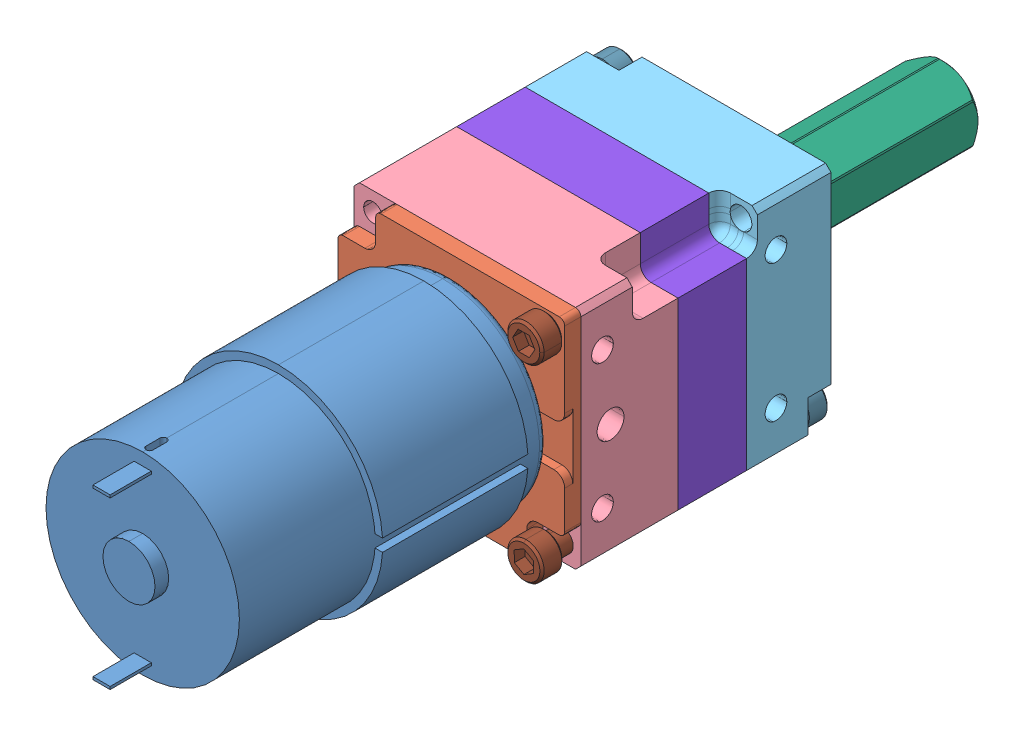
SolidWorks assembly VersaPlanetary v1 Single Stage 10_1 with RS 550 .step, configuration Default. Lengths in mm.
Overall size (42.53 42 155.97).
31 component instances, 20 part files, 0 mates.
Components (placement in the parent):
- 217-2625-100.step-1: 217-2625-100.step [Default] at (0 0 -18.467) x (0 1 0) z (0 0 1) size (39.22 38.88 12.7)
  - 217-2625-008 Rev1.step-1: 217-2625-008 Rev1.step [Default] at origin size (34.7 34.7 4.7)
  - 217-2625-010 Rev1.step-1: 217-2625-010 Rev1.step [Default] at (0 10.193 3.65) x (0.999813 0.019336 0) z (0 0 1) size (4 4 12)
  - 217-2625-010 Rev1.step-2: 217-2625-010 Rev1.step [Default] at (8.691 -5.3258 3.65) size (4 4 12)
  - 217-2625-010 Rev1.step-3: 217-2625-010 Rev1.step [Default] at (-8.691 -5.3258 3.65) size (4 4 12)
  - 217-2625-005 Rev1_Planet_Revolving_Follower01.step-1: 217-2625-005 Rev1_Planet_Revolving_Follower01.step [Default] at (8.691 -5.3258 6.35) x (0.932816 0.360354 0) z (0 0 1) size (16.89 16.89 8)
  - 217-2625-005 Rev1_Planet_Revolving_Follower01.step-2: 217-2625-005 Rev1_Planet_Revolving_Follower01.step [Default] at (-8.691 -5.3258 6.35) x (-0.932788 -0.360426 0) z (0 0 1) size (16.89 16.89 8)
  - 217-2625-005 Rev1_Planet_Revolving_Follower01.step-3: 217-2625-005 Rev1_Planet_Revolving_Follower01.step [Default] at (0 10.193 6.35) x (0.893583 0.448898 0) z (0 0 1) size (16.89 16.89 8)
- 217-2625-001 Rev1.step-1: 217-2625-001 Rev1.step [Default] at origin size (42 42 18)
- 217-2625-002 Rev1.step-1: 217-2625-002 Rev1.step [Default] at (0 0 -16.7) size (42 42 17.12)
- 217-2625-003 Rev1.step-1: 217-2625-003 Rev1.step [Default] at (0 0 -30.9478) x (1 0 0) z (0 0 -1) size (17 17 64.11)
- 217-2625-009 Rev1.step-1: 217-2625-009 Rev1.step [Default] at (0 0 -3.48) x (0 -1 0) z (0 0 -1) size (18 18 13)
- 217-2816-001 Rev1.step-1: 217-2816-001 Rev1.step [Default] at (0 0 -16.85) x (1 0 0) z (0 0 -1) size (42 42 14.51)
- 217-2625-007 Rev1_Sun_Driver01.step-1: 217-2625-007 Rev1_Sun_Driver01.step [Default] at (0 0 -11.767) x (0.055822 0.998441 0) z (0 0 1) size (15.27 15.27 12.71)
- 217-2625-012 Rev1.step-1: 217-2625-012 Rev1.step [Default] at (0 0 -2.4942) size (8.01 7.94 7.5)
- SSA_SSA0832-0500ZC.step-1: SSA_SSA0832-0500ZC.step [Default] at (-17.4921 -17.5079 10.5) x (0.008716 -0.999962 0) z (-0.999962 -0.008716 0) size (6.73 16.76 6.73)
- SSA_SSAM3-0008ZC.step-1: SSA_SSAM3-0008ZC.step [Default] at (0 12.5 17.025) x (-0.999994 -0.00359 0) z (0.00359 -0.999994 0) size (5.5 11 5.5)
- SSA_SSAM3-0008ZC.step-2: SSA_SSAM3-0008ZC.step [Default] at (0 -12.5 17.025) x (-0.960339 -0.278833 0) z (0.278833 -0.960339 0) size (5.5 11 5.5)
- 217-2742.step-1: 217-2742.step [Default] at (0 0 -30.4002) x (0 0 1) z (-1 0 0) size (7 28 28)
- 217-2742.step-2: 217-2742.step [Default] at (0 0 -38.7002) x (0 0 1) z (-0.997393 0.072165 0) size (7 28 28)
- SSA_SSA0832-1250ZC.step-1: SSA_SSA0832-1250ZC.step [Default] at (17.5 -17.5 -34.561) x (1 0 0) z (0 1 0) size (6.73 35.81 6.73)
- SSA_SSA0832-1250ZC.step-2: SSA_SSA0832-1250ZC.step [Default] at (-17.5 17.5 -34.561) x (1 0 0) z (0 1 0) size (6.73 35.81 6.73)
- SSS1032-0125ZB_94105A824.step-1: SSS1032-0125ZB_94105A824.step [Default] at (-6.908 0 1.995) x (0 -0.92485 0.380331) z (-1 0 0) size (4.84 4.84 3.18)
- 217-2625-018 Rev1_98541A410.step-1: 217-2625-018 Rev1_98541A410.step [Default] at (0 0 -22.7954) x (0 0 -1) z (0.980859 -0.194721 0) size (1 19.6 17.4)
- 217-2625-017 Rev1_9714K61.step-1: 217-2625-017 Rev1_9714K61.step [Default] at (0 0 -31.4002) x (-0.695225 0.718792 0) z (-0.718792 -0.695225 0) size (28.51 4.98 27.43)
- PINL-M020-006-S.step-1: PINL-M020-006-S.step [Default] at (-18.5 13.6657 -9.5) x (0 0 -1) z (1 0 0) size (6 2 2)
- PINL-M020-006-S.step-2: PINL-M020-006-S.step [Default] at (-18.5 13.6657 -22.2) x (0 0 -1) z (0.23951 -0.970894 0) size (6 2 2)
- BaneBots RS550.step-1: BaneBots RS550.step [Default] at (0 0 60.538) x (0 1 0) z (0 0 -1) size (38.61 38.57 77.9)
- SSA_SSA0832-0500ZC.step-2: SSA_SSA0832-0500ZC.step [Default] at (17.5079 -17.4921 10.5) x (0.999962 0.008716 0) z (0.008716 -0.999962 0) size (6.73 16.76 6.73)
- SSA_SSA0832-0500ZC.step-3: SSA_SSA0832-0500ZC.step [Default] at (17.4921 17.5079 10.5) x (-0.008716 0.999962 0) z (0.999962 0.008716 0) size (6.73 16.76 6.73)
- 217-2822-001 Rev4.step-1: 217-2822-001 Rev4.step [Default] at (0 0 9) size (42 42 4.8)
